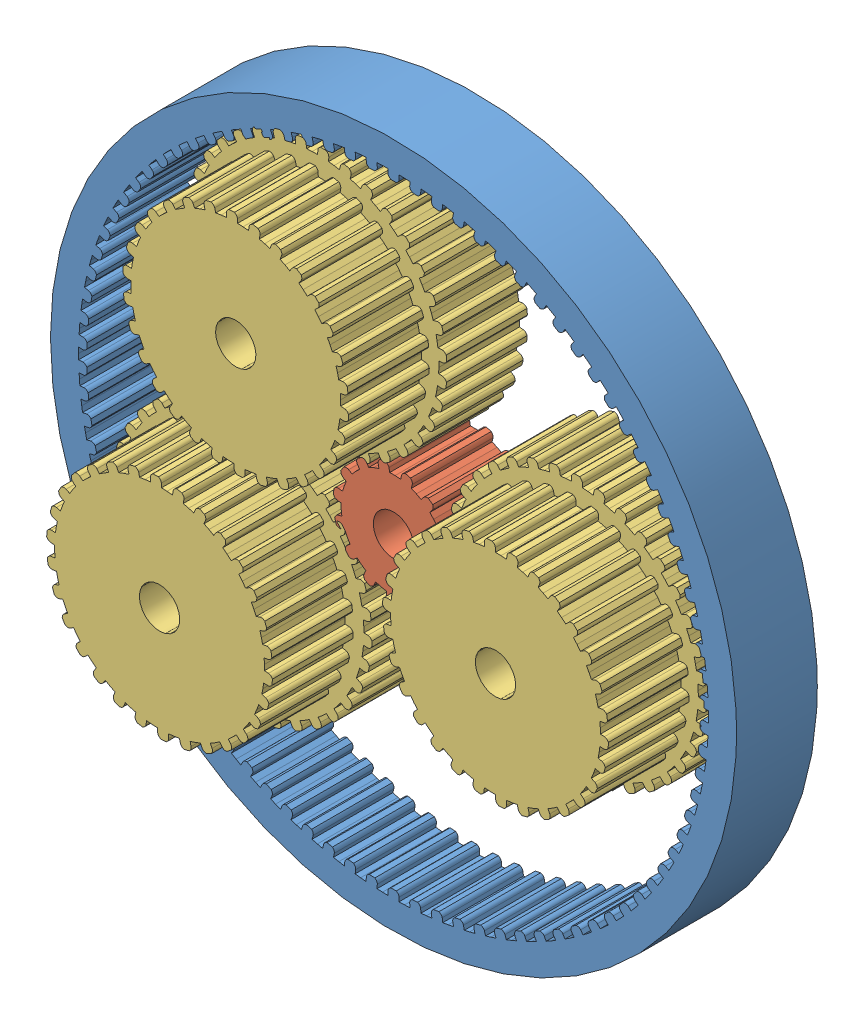
SolidWorks assembly Assem1, configuration Default. Lengths in mm.
Overall size (85 85 20).
5 component instances, 3 part files, 8 mates.
Components (placement in the parent):
- carrier-1: carrier [Default] at (-10.7549 -3.2148 85) size (85 85 10)
- sun-1: sun [Default] at (-10.7549 -3.2148 85) x (0.472312 -0.881431 0) z (-0.881431 -0.472312 0) size (14.96 10 14.88)
- planet-1: planet [Default] at (-20.3004 17.5784 85) x (-0.999391 -0.034882 0) z (-0.034882 0.999391 0) size (32.32 20 32.29)
- planet-2: planet [Default] at (-29.7371 -15.5044 85) x (0.470505 0.882397 0) z (0.882397 -0.470505 0) size (32.32 20 32.29)
- planet-3: planet [Default] at (11.8784 -1.7361 85) x (-0.966021 -0.258462 0) z (-0.258462 0.966021 0) size (32.32 20 32.29)
Mates (geometry in assembly coordinates):
- Coincident16: coincident: plane of planet-1 through (-22.0188 1.8965 85) normal (0 0 -1); plane of planet-3 through (13.7262 -17.4033 85) normal (0 0 -1)
- Coincident17: coincident: plane of planet-2 through (-42.448 -6.1607 85) normal (0 0 -1); plane of planet-3 through (13.7262 -17.4033 85) normal (0 0 -1)
- Coincident18: coincident: plane of carrier-1 through (-10.7549 -3.2148 85) normal (0 0 -1); plane of planet-3 through (13.7262 -17.4033 85) normal (0 0 -1)
- Coincident19: coincident: plane of carrier-1 through (-10.7549 -3.2148 85) normal (0 0 -1); plane of sun-1 through (-10.7549 -3.2148 85) normal (0 0 -1)
- Concentric4: concentric: circle of carrier-1; circle of sun-1
- GearMate3: gear = 5 : 5 mm: circle of planet-3; circle of sun-1
- GearMate4: gear = 5 : 5 mm: circle of sun-1; circle of planet-2
- GearMate5: gear = 5 : 5 mm: circle of planet-1; circle of sun-1
